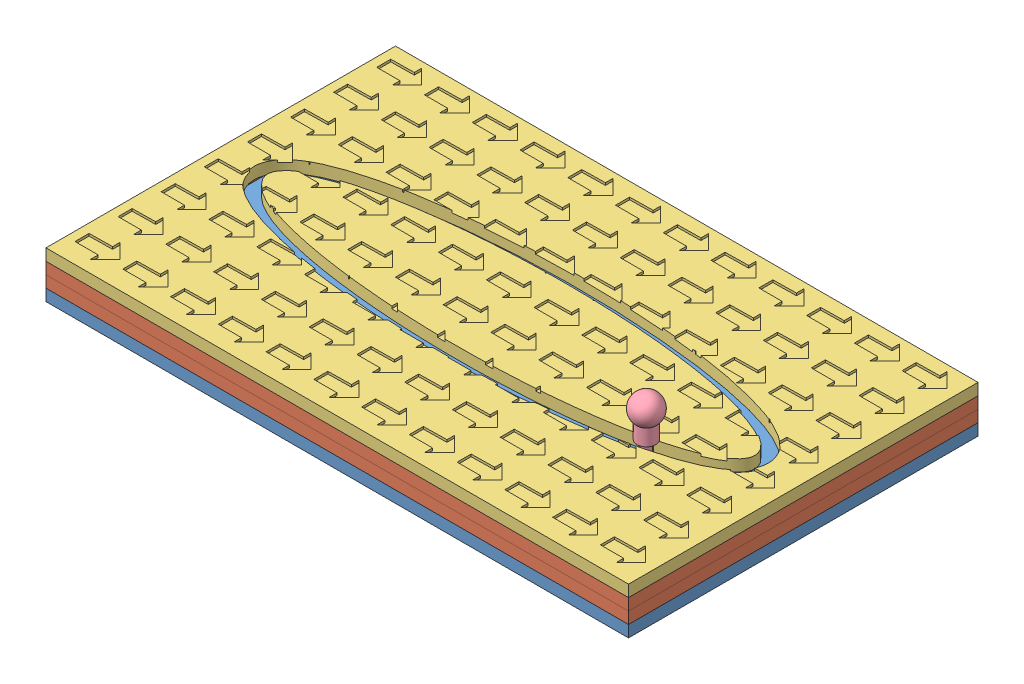
SolidWorks assembly assembly, configuration Default. Lengths in mm.
Overall size (250 39.63 150).
6 component instances, 5 part files, 9 mates.
Components (placement in the parent):
- base1-1: base1 [Default] at (-49.7046 107.1468 237.7868) size (250 5 150)
- base2-1: base2 [Default] at (-49.7046 112.1468 237.7868) size (250 5 150)
- base2-2: base2 [Default] at (-49.7046 117.1468 237.7868) size (250 5 150)
- base3-1: base3 [Default] at (-49.7046 122.1468 237.7868) size (250 5 150)
- slider-1: slider [Default] at (152.326 117.1468 182.1401) x (0.774448 0 -0.632637) z (0.632637 0 0.774448) size (12.13 29.63 12.13)
- washer clip-1: washer clip [Default] at (152.326 117.1468 182.1401) x (0.998664 0 -0.051679) z (0.051679 0 0.998664) size (11.02 5 8)
Mates (geometry in assembly coordinates):
- Coincident1: coincident: line of base1-1 through (200.2954 112.1468 237.7868) axis (0 0 -1); line of base2-1 through (200.2954 112.1468 237.7868) axis (0 0 -1)
- Coincident2: coincident: line of base1-1 through (-49.7046 112.1468 237.7868) axis (1 0 0); line of base2-1 through (-49.7046 112.1468 237.7868) axis (1 0 0)
- Coincident3: coincident: line of base2-1 through (200.2954 117.1468 237.7868) axis (0 0 -1); line of base2-2 through (200.2954 117.1468 237.7868) axis (0 0 -1)
- Coincident4: coincident: line of base2-1 through (-49.7046 117.1468 237.7868) axis (1 0 0); line of base2-2 through (-49.7046 117.1468 237.7868) axis (1 0 0)
- Coincident5: coincident: line of base2-2 through (200.2954 122.1468 237.7868) axis (0 0 -1); line of base3-1 through (200.2954 122.1468 237.7868) axis (0 0 -1)
- Coincident6: coincident: line of base2-2 through (-49.7046 122.1468 237.7868) axis (1 0 0); line of base3-1 through (-49.7046 122.1468 237.7868) axis (1 0 0)
- Coincident7: coincident: circle of slider-1; circle of washer clip-1
- Coincident8: coincident: plane of base3-1 through (-49.7046 122.1468 237.7868) normal (0 -1 0); plane of washer clip-1 through (-33.1406 122.1468 163.4025) normal (0 1 0)
- Tangent3: tangent: face of base3-1; cylinder of slider-1 through (-33.1406 129.1468 163.4025) axis (0 -1 0) radius 2.2
